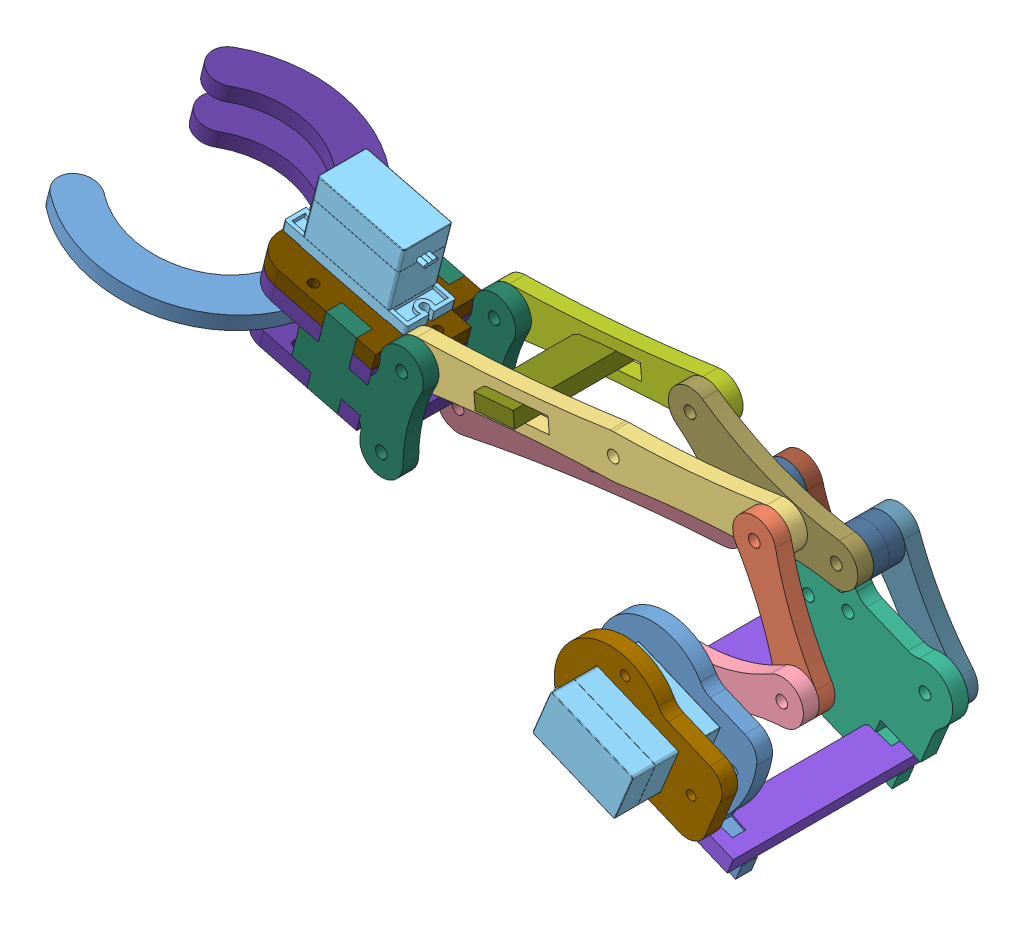
SolidWorks assembly MDP Arm assem, configuration Default. Lengths in mm.
Overall size (197.5 89.05 74.35).
26 component instances, 19 part files, 64 mates.
Components (placement in the parent):
- Sideplates-2: Sideplates [Default] at (-69.5439 -81.677 -1.4429) x (0.924138 -0.38206 0) z (0 0 1) size (46.09 35.64 4)
- Y-Link 1-1: Y-Link 1 [Default] at (-26.169 -55.853 -5.7429) x (-0.930609 -0.366014 0) z (0.366014 -0.930609 0) size (11 4 41)
- Y-long link MDP-1: Y-long link MDP [Default] at (-37.1494 -27.9347 -13.7429) x (-0.083915 0.996473 0) z (0.996473 0.083915 0) size (11 4 101)
- Y-Servo Link-1: Y-Servo Link [Default] at (-40.5379 -60.1582 -5.7429) x (0.287013 -0.957927 0) z (0 0 1) size (15.2 43.1 4)
- microservoSG90-2: microservoSG90 [Default] at (-50.1937 -66.4119 24.8571) x (0.924138 -0.38206 0) z (0.38206 0.924138 0) size (32.3 29.8 12.5)
- Sideplates Fixed Joint-2: Sideplates Fixed Joint [Default] at (-69.5439 -81.677 -41.2429) x (0.924138 -0.38206 0) z (0 0 1) size (51.21 35.64 4)
- X-long link MDP-1: X-long link MDP [Default] at (-77.0084 -31.2913 -33.2429) x (0.083915 -0.996473 0) z (0.996473 0.083915 0) size (11 4 61)
- Slide spacer-1: Slide spacer [Default] at (-41.4929 -88.9456 -19.1624) x (-0.924138 0.38206 0) z (0.38206 0.924138 0) size (10 50.4 4)
- Slide spacer-2: Slide spacer [Default] at (-58.5894 -81.8775 -19.1624) x (0.924138 -0.38206 0) z (0.38206 0.924138 0) size (10 50.4 4)
- Servo Mount-1: Servo Mount [Default] at (-67.9595 -69.888 9.2571) x (0.924138 -0.38206 0) z (0 0 1) size (42.53 24.14 4)
- 4mm Spacer-1: 4mm Spacer [Default] at (-64.5691 -46.9522 -37.2429) x (0.999988 -0.004954 0) z (-0.004954 -0.999988 0) size (11 4 11)
- Fixed Link auto Stabilizer-1: Fixed Link auto Stabilizer [Default] at (-54.9068 -64.4634 -41.2429) x (-0.875557 -0.483116 0) z (0.483116 -0.875557 0) size (11 4 31)
- Stabilizer Triangle MDP-1: Stabilizer Triangle MDP [Default] at (-77.0084 -31.2913 -29.2429) x (-0.92944 0.368974 0) z (0 0 -1) size (51 20.97 4)
- Stabilizer link-2: Stabilizer link [Default] at (-131.9851 -55.8449 -29.2429) x (0.130775 -0.991412 0) z (-0.991412 -0.130775 0) size (11 4 79)
- Retractor Link-3: Retractor Link [Default] at (-39.8308 -46.0502 -41.2429) x (0.866354 0.49943 0) z (-0.49943 0.866354 0) size (11 4 40.15)
- Horizontalizer Connector MDP V2-1: Horizontalizer Connector MDP V2 [Default] at (-126.832 -35.487 -29.2429) x (-0.969425 0.245388 0) z (0 0 -1) size (30 32 4)
- 4mm Spacer-2: 4mm Spacer [Default] at (-64.5691 -46.9522 -41.2429) x (0.99967 0.025687 0) z (0.025687 -0.99967 0) size (11 4 11)
- 4mm Spacer-3: 4mm Spacer [Default] at (-39.8308 -46.0502 -37.2429) x (0.999974 0.007211 0) z (0.007211 -0.999974 0) size (11 4 11)
- 4mm Spacer-4: 4mm Spacer [Default] at (-39.8308 -46.0502 -41.2429) x (0.999988 -0.004954 0) z (-0.004954 -0.999988 0) size (11 4 11)
- Slide spacer MDP-1: Slide spacer MDP [Default] at (-109.7609 -32.0423 -23.4929) x (-0.996473 -0.083915 0) z (0.083915 -0.996473 0) size (10 32.9 4)
- Top Servo Holder-1: Top Servo Holder [Default] at (-168.7336 -42.4167 -5.7429) x (0 0 -1) z (-0.245388 -0.969425 0) size (43.75 81.79 4.1)
- microservoSG90-3: microservoSG90 [Default] at (-144.773 -13.4095 -19.4929) x (-0.969425 0.245388 0) z (0 0 1) size (32.3 29.8 12.5)
- bottom Servo Holder-2: bottom Servo Holder [Default] at (-165.8477 -30.9751 -33.2329) x (0 0 1) z (0.245388 0.969425 0) size (27.5 37.42 4)
- moving hand-1: moving hand [Default] at (-147.3378 -44.3254 -19.4929) x (0.140472 -0.035557 0.989446) z (-0.959194 0.242798 0.144902) size (35.47 4.1 71.94)
- Horizontalizer Connector MDP V2-2: Horizontalizer Connector MDP V2 [Default] at (-126.832 -35.487 -5.7329) x (-0.969425 0.245388 0) z (0 0 -1) size (30 32 4)
- Top Servo Holder-4: Top Servo Holder [Default] at (-165.838 -30.9775 -5.7429) x (0 0 -1) z (-0.245388 -0.969425 0) size (43.75 81.79 4.1)
Mates (geometry in assembly coordinates):
- Concentric2: concentric anti-aligned: cylinder of Y-Link 1-1 through (-26.169 -55.853 -9.7429) axis (0 0 1) radius 1.5; cylinder of Y-Servo Link-1 through (-26.169 -55.853 -1.7429) axis (0 0 -1) radius 1.5
- Coincident11: coincident anti-aligned: plane of Y-Link 1-1 through (12.6725 -32.5171 -5.7429) normal (0 0 1); plane of Y-Servo Link-1 through (-40.5379 -60.1582 -5.7429) normal (0 0 -1)
- Concentric5: concentric anti-aligned: cylinder of Y-Link 1-1 through (-37.1494 -27.9347 -9.7429) axis (0 0 1) radius 1.5; cylinder of Y-long link MDP-1 through (-37.1494 -27.9347 -9.7429) axis (0 0 -1) radius 1.5
- Coincident15: coincident anti-aligned: plane of Y-Link 1-1 through (12.6725 -32.5171 -9.7429) normal (0 0 -1); plane of Y-long link MDP-1 through (-96.9096 -241.8498 -9.7429) normal (0 0 1)
- Concentric10: concentric anti-aligned: cylinder of Y-Servo Link-1 through (-54.9068 -64.4634 -1.7429) axis (0 0 -1) radius 3.6; cylinder of microservoSG90-2 through (-54.9068 -64.4634 -4.9429) axis (0 0 1) radius 2.45
- Coincident25: coincident anti-aligned: plane of Y-Servo Link-1 through (-40.5379 -60.1582 -1.7429) normal (0 0 1); plane of microservoSG90-2 through (-49.593 -66.6602 -1.7429) normal (0 0 -1)
- Concentric36: concentric anti-aligned: cylinder of X-long link MDP-1 through (-126.832 -35.487 -37.2429) axis (0 0 1) radius 1.5; cylinder of Y-long link MDP-1 through (-126.832 -35.487 -9.7429) axis (0 0 -1) radius 1.5
- Concentric49: concentric anti-aligned: cylinder of Sideplates-2 through (-54.9068 -64.4634 2.5571) axis (0 0 -1) radius 6.21; cylinder of microservoSG90-2 through (-54.9068 -64.4634 -1.7429) axis (0 0 1) radius 6.2
- Coincident89: coincident anti-aligned: plane of Sideplates-2 through (-69.5439 -81.677 2.5571) normal (0 0 1); plane of microservoSG90-2 through (-50.1937 -66.4119 2.5571) normal (0 0 -1)
- Coincident91: coincident anti-aligned: plane of microservoSG90-2 through (-58.2677 -56.3649 9.2571) normal (-0.924138 0.38206 0); plane of Servo Mount-1 through (-64.4571 -71.336 13.2571) normal (0.924138 -0.38206 0)
- Parallel5: parallel anti-aligned: plane of microservoSG90-2 through (-58.2677 -56.3649 9.2571) normal (0.38206 0.924138 0); plane of Servo Mount-1 through (-61.7664 -54.9077 13.2571) normal (-0.38206 -0.924138 0)
- Coincident93: coincident anti-aligned: plane of microservoSG90-2 through (-50.1937 -66.4119 9.2571) normal (0 0 1); plane of Servo Mount-1 through (-67.9595 -69.888 9.2571) normal (0 0 -1)
- Concentric53: concentric anti-aligned: cylinder of Sideplates Fixed Joint-2 through (-54.9068 -64.4634 -37.2429) axis (0 0 -1) radius 1.5; cylinder of Fixed Link auto Stabilizer-1 through (-54.9068 -64.4634 -45.2429) axis (0 0 1) radius 1.5
- Concentric54: concentric aligned: cylinder of Fixed Link auto Stabilizer-1 through (-64.5691 -46.9522 -45.2429) axis (0 0 1) radius 1.5; cylinder of Stabilizer Triangle MDP-1 through (-64.5691 -46.9522 -33.2429) axis (0 0 1) radius 1.5
- Concentric55: concentric aligned: cylinder of X-long link MDP-1 through (-77.0084 -31.2913 -37.2429) axis (0 0 1) radius 1.5; cylinder of Stabilizer Triangle MDP-1 through (-77.0084 -31.2913 -33.2429) axis (0 0 1) radius 1.5
- Concentric56: concentric anti-aligned: cylinder of Y-long link MDP-1 through (-126.832 -35.487 -9.7429) axis (0 0 -1) radius 1.5; cylinder of X-long link MDP-1 through (-126.832 -35.487 -37.2429) axis (0 0 1) radius 1.5
- Concentric59: concentric anti-aligned: cylinder of Stabilizer Triangle MDP-1 through (-64.5691 -46.9522 -33.2429) axis (0 0 1) radius 1.5; cylinder of Stabilizer link-2 through (-64.5691 -46.9522 -25.2429) axis (0 0 -1) radius 1.5
- Concentric60: concentric anti-aligned: cylinder of Sideplates Fixed Joint-2 through (-25.2724 -71.3045 -37.2429) axis (0 0 -1) radius 1.5; cylinder of Retractor Link-3 through (-25.2724 -71.3045 -45.2429) axis (0 0 1) radius 1.5
- Concentric61: concentric aligned: cylinder of Stabilizer Triangle MDP-1 through (-39.8308 -46.0502 -33.2429) axis (0 0 1) radius 1.5; cylinder of Retractor Link-3 through (-39.8308 -46.0502 -45.2429) axis (0 0 1) radius 1.5
- Coincident95: coincident anti-aligned: plane of Sideplates Fixed Joint-2 through (-69.5439 -81.677 -41.2429) normal (0 0 -1); plane of Fixed Link auto Stabilizer-1 through (-44.916 -41.8187 -41.2429) normal (0 0 1)
- Coincident96: coincident anti-aligned: plane of Sideplates Fixed Joint-2 through (-69.5439 -81.677 -41.2429) normal (0 0 -1); plane of Retractor Link-3 through (-72.7285 -73.4266 -41.2429) normal (0 0 1)
- Coincident97: coincident anti-aligned: plane of Sideplates Fixed Joint-2 through (-69.5439 -81.677 -37.2429) normal (0 0 1); plane of X-long link MDP-1 through (-106.9307 175.0715 -37.2429) normal (0 0 -1)
- Coincident98: coincident anti-aligned: plane of X-long link MDP-1 through (-106.9307 175.0715 -33.2429) normal (0 0 1); plane of Stabilizer Triangle MDP-1 through (-77.0084 -31.2913 -33.2429) normal (0 0 -1)
- Coincident103: coincident anti-aligned: plane of Stabilizer Triangle MDP-1 through (-77.0084 -31.2913 -29.2429) normal (0 0 1); plane of Stabilizer link-2 through (-145.3254 175.2829 -29.2429) normal (0 0 -1)
- Concentric72: concentric anti-aligned: cylinder of 4mm Spacer-1 through (-64.5691 -46.9522 -33.2429) axis (0 0 -1) radius 1.5; cylinder of Stabilizer Triangle MDP-1 through (-64.5691 -46.9522 -33.2429) axis (0 0 1) radius 1.5
- Coincident107: coincident anti-aligned: plane of 4mm Spacer-1 through (-64.5691 -46.9522 -33.2429) normal (0 0 1); plane of Stabilizer Triangle MDP-1 through (-77.0084 -31.2913 -33.2429) normal (0 0 -1)
- Concentric73: concentric aligned: cylinder of 4mm Spacer-1 through (-64.5691 -46.9522 -33.2429) axis (0 0 -1) radius 1.5; cylinder of 4mm Spacer-2 through (-64.5691 -46.9522 -37.2429) axis (0 0 -1) radius 1.5
- Coincident108: coincident anti-aligned: plane of Fixed Link auto Stabilizer-1 through (-44.916 -41.8187 -41.2429) normal (0 0 1); plane of 4mm Spacer-2 through (-64.5691 -46.9522 -41.2429) normal (0 0 -1)
- Concentric74: concentric anti-aligned: cylinder of Stabilizer Triangle MDP-1 through (-39.8308 -46.0502 -33.2429) axis (0 0 1) radius 1.5; cylinder of 4mm Spacer-3 through (-39.8308 -46.0502 -33.2429) axis (0 0 -1) radius 1.5
- Concentric75: concentric aligned: circle of Retractor Link-3; cylinder of 4mm Spacer-4 through (-39.8308 -46.0502 -37.2429) axis (0 0 -1) radius 1.5
- Coincident109: coincident anti-aligned: plane of Stabilizer Triangle MDP-1 through (-77.0084 -31.2913 -33.2429) normal (0 0 -1); plane of 4mm Spacer-3 through (-39.8308 -46.0502 -33.2429) normal (0 0 1)
- Coincident110: coincident anti-aligned: plane of 4mm Spacer-3 through (-39.8308 -46.0502 -37.2429) normal (0 0 -1); plane of 4mm Spacer-4 through (-39.8308 -46.0502 -37.2429) normal (0 0 1)
- Coincident118: coincident anti-aligned: plane of Y-long link MDP-1 through (-103.5827 -31.5221 -9.7429) normal (0.996473 0.083915 0); plane of Slide spacer MDP-1 through (-103.2471 -35.508 -23.4929) normal (-0.996473 -0.083915 0)
- Coincident119: coincident anti-aligned: plane of X-long link MDP-1 through (-103.5827 -31.5221 -37.2429) normal (0.083915 -0.996473 0); plane of Slide spacer MDP-1 through (-109.7609 -32.0423 -23.4929) normal (-0.083915 0.996473 0)
- Coincident120: coincident: plane of Y-long link MDP-1 through (-96.9096 -241.8498 -13.7429) normal (0 0 -1); line of Slide spacer MDP-1 through (-103.2471 -35.508 -13.7429) axis (-0.083915 0.996473 0)
- Concentric82: concentric anti-aligned: cylinder of Y-long link MDP-1 through (-126.832 -35.487 -9.7429) axis (0 0 -1) radius 1.5; cylinder of Horizontalizer Connector MDP V2-2 through (-126.832 -35.487 -9.7329) axis (0 0 1) radius 1.5
- Concentric83: concentric anti-aligned: cylinder of Stabilizer link-2 through (-131.9851 -55.8449 -25.2429) axis (0 0 -1) radius 1.5; cylinder of Horizontalizer Connector MDP V2-2 through (-131.9851 -55.8449 -9.7329) axis (0 0 1) radius 1.5
- Coincident138: coincident anti-aligned: plane of X-long link MDP-1 through (-106.9307 175.0715 -33.2429) normal (0 0 1); plane of Horizontalizer Connector MDP V2-1 through (-126.832 -35.487 -33.2429) normal (0 0 -1)
- Concentric84: concentric aligned: cylinder of X-long link MDP-1 through (-126.832 -35.487 -37.2429) axis (0 0 1) radius 1.5; cylinder of Horizontalizer Connector MDP V2-1 through (-126.832 -35.487 -33.2429) axis (0 0 1) radius 1.5
- Concentric85: concentric anti-aligned: cylinder of Stabilizer link-2 through (-131.9851 -55.8449 -25.2429) axis (0 0 -1) radius 1.5; cylinder of Horizontalizer Connector MDP V2-1 through (-131.9851 -55.8449 -33.2429) axis (0 0 1) radius 1.5
- Coincident142: coincident anti-aligned: plane of microservoSG90-3 through (-149.2391 -31.053 -19.4929) normal (-0.245388 -0.969425 0); plane of bottom Servo Holder-2 through (-164.8662 -27.0974 -33.2329) normal (0.245388 0.969425 0)
- Coincident143: coincident anti-aligned: plane of microservoSG90-3 through (-139.2906 -37.8005 -25.6929) normal (0.969425 -0.245388 0); plane of bottom Servo Holder-2 through (-138.2846 -33.8259 -33.2329) normal (-0.969425 0.245388 0)
- Coincident144: coincident anti-aligned: plane of microservoSG90-3 through (-137.6465 -31.3054 -25.6929) normal (0 0 -1); plane of bottom Servo Holder-2 through (-164.8662 -27.0974 -25.6929) normal (0 0 1)
- Coincident145: coincident anti-aligned: plane of Horizontalizer Connector MDP V2-1 through (-131.0036 -51.9672 -33.2429) normal (-0.245388 -0.969425 0); plane of Top Servo Holder-1 through (-168.7336 -42.4167 -5.7429) normal (0.245388 0.969425 0)
- Coincident146: coincident aligned: plane of Horizontalizer Connector MDP V2-1 through (-126.832 -35.487 -33.2429) normal (0 0 -1); plane of Top Servo Holder-1 through (-169.7152 -46.2944 -33.2429) normal (0 0 -1)
- Coincident147: coincident anti-aligned: plane of Horizontalizer Connector MDP V2-1 through (-137.3049 -50.3722 -29.2429) normal (-0.969425 0.245388 0); plane of Top Servo Holder-1 through (-138.2864 -54.2499 -5.7429) normal (0.969425 -0.245388 0)
- Coincident148: coincident aligned: plane of Horizontalizer Connector MDP V2-1 through (-126.832 -35.487 -33.2429) normal (0 0 -1); plane of Top Servo Holder-4 through (-166.8196 -34.8552 -33.2429) normal (0 0 -1)
- Coincident149: coincident anti-aligned: plane of Horizontalizer Connector MDP V2-1 through (-137.9804 -32.665 -33.2429) normal (0.969425 -0.245388 0); plane of Top Servo Holder-4 through (-140.238 -41.5838 -5.7429) normal (-0.969425 0.245388 0)
- Coincident150: coincident anti-aligned: plane of Horizontalizer Connector MDP V2-1 through (-140.238 -41.5838 -29.2429) normal (0.245388 0.969425 0); plane of Top Servo Holder-4 through (-166.8196 -34.8552 -5.7429) normal (-0.245388 -0.969425 0)
- Coincident151: coincident anti-aligned: plane of bottom Servo Holder-2 through (-165.8477 -30.9751 -33.2329) normal (-0.245388 -0.969425 0); plane of Top Servo Holder-4 through (-165.838 -30.9775 -5.7429) normal (0.245388 0.969425 0)
- Concentric86: concentric aligned: cylinder of microservoSG90-3 through (-146.3562 -40.4477 -19.4929) axis (0.245388 0.969425 0) radius 6.2; cylinder of Top Servo Holder-4 through (-146.2581 -40.0599 -19.4929) axis (0.245388 0.969425 0) radius 6.21
- Parallel6: parallel anti-aligned: plane of Horizontalizer Connector MDP V2-1 through (-137.9804 -32.665 -33.2429) normal (0.969425 -0.245388 0); plane of bottom Servo Holder-2 through (-138.2846 -33.8259 -33.2329) normal (-0.969425 0.245388 0)
- Concentric87: concentric anti-aligned: cylinder of microservoSG90-3 through (-147.1415 -43.5498 -19.4929) axis (0.245388 0.969425 0) radius 2.45; cylinder of moving hand-1 through (-146.3562 -40.4477 -19.4929) axis (-0.245388 -0.969425 0) radius 3.6
- Coincident154: coincident anti-aligned: plane of microservoSG90-3 through (-151.9304 -39.0367 -19.4929) normal (-0.245388 -0.969425 0); plane of moving hand-1 through (-146.3562 -40.4477 -19.4929) normal (0.245388 0.969425 0)
- Coincident155: coincident anti-aligned: plane of bottom Servo Holder-2 through (-164.8662 -27.0974 -9.7329) normal (0 0 1); plane of Horizontalizer Connector MDP V2-2 through (-126.832 -35.487 -9.7329) normal (0 0 -1)
- Coincident163: coincident aligned: plane of Sideplates-2 through (-57.509 -52.5667 2.5571) normal (0.38206 0.924138 0); plane of Servo Mount-1 through (-60.3184 -51.4052 13.2571) normal (0.38206 0.924138 0)
- Coincident164: coincident anti-aligned: plane of Sideplates-2 through (-68.0156 -77.9805 2.5571) normal (0.38206 0.924138 0); plane of Slide spacer-2 through (-58.5894 -81.8775 -19.1624) normal (-0.38206 -0.924138 0)
- Coincident165: coincident anti-aligned: plane of Sideplates-2 through (-65.8473 -83.2052 2.5571) normal (-0.924138 0.38206 0); plane of Slide spacer-2 through (-62.7908 -75.8121 -19.1624) normal (0.924138 -0.38206 0)
- Coincident166: coincident anti-aligned: plane of Sideplates Fixed Joint-2 through (-65.8473 -83.2052 -37.2429) normal (-0.924138 0.38206 0); plane of Slide spacer-2 through (-62.7908 -75.8121 -19.1624) normal (0.924138 -0.38206 0)
- Coincident167: coincident anti-aligned: plane of Sideplates Fixed Joint-2 through (-68.0156 -77.9805 -37.2429) normal (0.38206 0.924138 0); plane of Slide spacer-2 through (-58.5894 -81.8775 -19.1624) normal (-0.38206 -0.924138 0)
- Coincident168: coincident anti-aligned: plane of Sideplates-2 through (-68.0156 -77.9805 2.5571) normal (0.38206 0.924138 0); plane of Slide spacer-1 through (-41.4929 -88.9456 -19.1624) normal (-0.38206 -0.924138 0)
- Coincident169: coincident anti-aligned: plane of Sideplates-2 through (-37.2914 -95.0109 2.5571) normal (0.924138 -0.38206 0); plane of Slide spacer-1 through (-34.235 -87.6178 -19.1624) normal (-0.924138 0.38206 0)
- Distance1: distance = 43.8 mm anti-aligned: plane of Sideplates Fixed Joint-2 through (-69.5439 -81.677 -41.2429) normal (0 0 -1); plane of Sideplates-2 through (-69.5439 -81.677 2.5571) normal (0 0 1)
- Coincident171: coincident aligned: plane of Slide spacer-1 through (-39.9646 -85.249 -44.3624) normal (0 0 -1); plane of Slide spacer-2 through (-57.0612 -78.1809 -44.3624) normal (0 0 -1)
